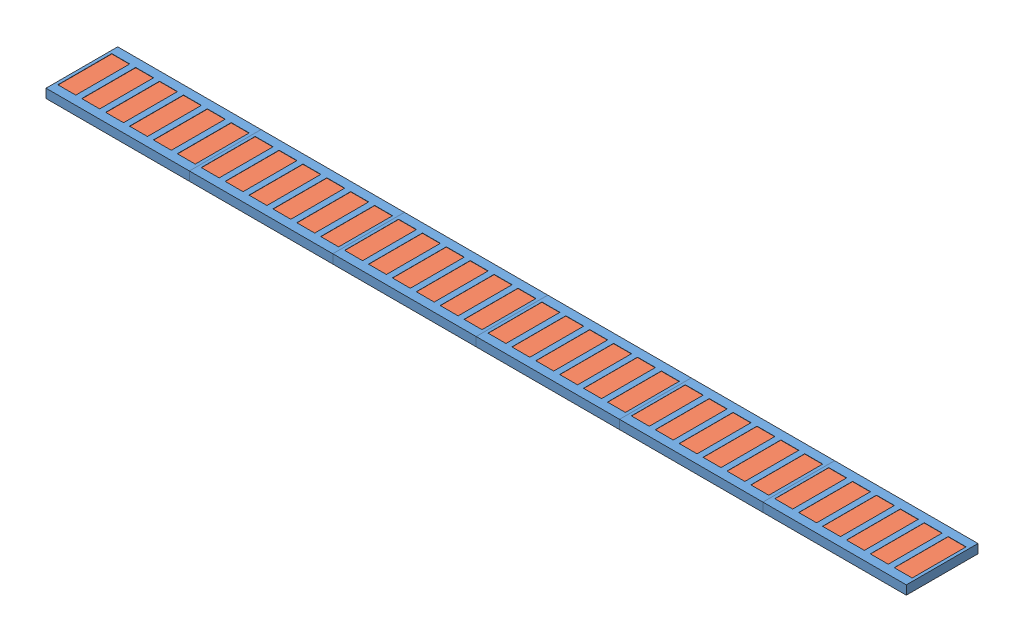
SolidWorks assembly МагнитнаяДорожка_10, configuration По умолчанию. Lengths in mm.
Overall size (480 11.1 40).
42 component instances, 2 part files, 9 mates.
Components (placement in the parent):
- magnete plate-1: magnete plate [По умолчанию] at (0.835 0 0) size (80 11.1 40)
- magnete plate-2: magnete plate [По умолчанию] at (80.835 0 0) size (80 11.1 40)
- magnete plate-3: magnete plate [По умолчанию] at (160.835 0 0) size (80 11.1 40)
- magnete plate-4: magnete plate [По умолчанию] at (240.835 0 0) size (80 11.1 40)
- magnete_30-1: magnete_30 [По умолчанию] at (-32.455 2.9 0) x (0 0 -1) z (1 0 0) size (30 2 10)
- magnete_30-2: magnete_30 [По умолчанию] at (-19.125 2.9 0) x (0 0 -1) z (1 0 0) size (30 2 10)
- magnete_30-3: magnete_30 [По умолчанию] at (-5.795 2.9 0) x (0 0 -1) z (1 0 0) size (30 2 10)
- magnete_30-4: magnete_30 [По умолчанию] at (7.535 2.9 0) x (0 0 -1) z (1 0 0) size (30 2 10)
- magnete_30-5: magnete_30 [По умолчанию] at (20.865 2.9 0) x (0 0 -1) z (1 0 0) size (30 2 10)
- magnete_30-6: magnete_30 [По умолчанию] at (34.195 2.9 0) x (0 0 -1) z (1 0 0) size (30 2 10)
- magnete_30-7: magnete_30 [По умолчанию] at (47.525 2.9 0) x (0 0 -1) z (1 0 0) size (30 2 10)
- magnete_30-8: magnete_30 [По умолчанию] at (60.855 2.9 0) x (0 0 -1) z (1 0 0) size (30 2 10)
- magnete_30-9: magnete_30 [По умолчанию] at (74.185 2.9 0) x (0 0 -1) z (1 0 0) size (30 2 10)
- magnete_30-10: magnete_30 [По умолчанию] at (87.515 2.9 0) x (0 0 -1) z (1 0 0) size (30 2 10)
- magnete_30-11: magnete_30 [По умолчанию] at (100.845 2.9 0) x (0 0 -1) z (1 0 0) size (30 2 10)
- magnete_30-12: magnete_30 [По умолчанию] at (114.175 2.9 0) x (0 0 -1) z (1 0 0) size (30 2 10)
- magnete_30-13: magnete_30 [По умолчанию] at (127.505 2.9 0) x (0 0 -1) z (1 0 0) size (30 2 10)
- magnete_30-14: magnete_30 [По умолчанию] at (140.835 2.9 0) x (0 0 -1) z (1 0 0) size (30 2 10)
- magnete_30-15: magnete_30 [По умолчанию] at (154.165 2.9 0) x (0 0 -1) z (1 0 0) size (30 2 10)
- magnete_30-16: magnete_30 [По умолчанию] at (167.495 2.9 0) x (0 0 -1) z (1 0 0) size (30 2 10)
- magnete_30-17: magnete_30 [По умолчанию] at (180.825 2.9 0) x (0 0 -1) z (1 0 0) size (30 2 10)
- magnete_30-18: magnete_30 [По умолчанию] at (194.155 2.9 0) x (0 0 -1) z (1 0 0) size (30 2 10)
- magnete_30-19: magnete_30 [По умолчанию] at (207.485 2.9 0) x (0 0 -1) z (1 0 0) size (30 2 10)
- magnete_30-20: magnete_30 [По умолчанию] at (220.815 2.9 0) x (0 0 -1) z (1 0 0) size (30 2 10)
- magnete_30-21: magnete_30 [По умолчанию] at (234.145 2.9 0) x (0 0 -1) z (1 0 0) size (30 2 10)
- magnete_30-22: magnete_30 [По умолчанию] at (247.475 2.9 0) x (0 0 -1) z (1 0 0) size (30 2 10)
- magnete_30-23: magnete_30 [По умолчанию] at (260.805 2.9 0) x (0 0 -1) z (1 0 0) size (30 2 10)
- magnete_30-24: magnete_30 [По умолчанию] at (274.135 2.9 0) x (0 0 -1) z (1 0 0) size (30 2 10)
- magnete_30-25: magnete_30 [По умолчанию] at (287.465 2.9 0) x (0 0 -1) z (1 0 0) size (30 2 10)
- magnete_30-26: magnete_30 [По умолчанию] at (300.795 2.9 0) x (0 0 -1) z (1 0 0) size (30 2 10)
- magnete_30-27: magnete_30 [По умолчанию] at (314.125 2.9 0) x (0 0 -1) z (1 0 0) size (30 2 10)
- magnete_30-28: magnete_30 [По умолчанию] at (327.455 2.9 0) x (0 0 -1) z (1 0 0) size (30 2 10)
- magnete_30-29: magnete_30 [По умолчанию] at (340.785 2.9 0) x (0 0 -1) z (1 0 0) size (30 2 10)
- magnete_30-30: magnete_30 [По умолчанию] at (354.115 2.9 0) x (0 0 -1) z (1 0 0) size (30 2 10)
- magnete_30-31: magnete_30 [По умолчанию] at (367.445 2.9 0) x (0 0 -1) z (1 0 0) size (30 2 10)
- magnete_30-32: magnete_30 [По умолчанию] at (380.775 2.9 0) x (0 0 -1) z (1 0 0) size (30 2 10)
- magnete_30-33: magnete_30 [По умолчанию] at (394.105 2.9 0) x (0 0 -1) z (1 0 0) size (30 2 10)
- magnete_30-34: magnete_30 [По умолчанию] at (407.435 2.9 0) x (0 0 -1) z (1 0 0) size (30 2 10)
- magnete_30-35: magnete_30 [По умолчанию] at (420.765 2.9 0) x (0 0 -1) z (1 0 0) size (30 2 10)
- magnete_30-36: magnete_30 [По умолчанию] at (434.095 2.9 0) x (0 0 -1) z (1 0 0) size (30 2 10)
- magnete plate-5: magnete plate [По умолчанию] at (320.835 0 0) size (80 11.1 40)
- magnete plate-6: magnete plate [По умолчанию] at (400.835 0 0) size (80 11.1 40)
Mates (geometry in assembly coordinates):
- Совпадение1: coincident aligned: plane of magnete plate edge-1 through (40.835 5 20) normal (0 0 1); plane of magnete plate-1 through (120.835 5 20) normal (0 0 1)
- Совпадение2: coincident anti-aligned: plane of magnete plate edge-1 through (40.835 5 20) normal (1 0 0); plane of magnete plate-1 through (40.835 5 20) normal (-1 0 0)
- Совпадение3: coincident aligned: plane of magnete plate edge-1 through (0 5 0) normal (0 1 0); plane of magnete plate-1 through (80.835 5 0) normal (0 1 0)
- Совпадение4: coincident anti-aligned: plane of magnete plate-4 through (360.835 5 20) normal (1 0 0); plane of magnete plate edge-2 through (360.835 5 -20) normal (-1 0 0)
- Совпадение6: coincident aligned: plane of magnete plate-4 through (320.835 5 0) normal (0 1 0); plane of magnete plate edge-2 through (401.67 5 0) normal (0 1 0)
- Совпадение7: coincident aligned: plane of magnete plate-4 through (360.835 5 20) normal (0 0 1); plane of magnete plate edge-2 through (360.835 5 20) normal (0 0 1)
- Расстояние1: distance = 0.05 mm anti-aligned: plane of magnete_30-1 through (-37.455 4.9 -15) normal (-1 0 0); plane of magnete plate-1 through (-37.505 2.9 -15.05) normal (1 0 0)
- Расстояние2: distance = 0.05 mm anti-aligned: plane of magnete_30-1 through (-27.455 4.9 15) normal (0 0 1); plane of magnete plate edge-1 through (-37.505 2.9 15.05) normal (0 0 -1)
- Совпадение10: coincident anti-aligned: plane of magnete plate edge-1 through (0 2.9 0) normal (0 1 0); plane of magnete_30-1 through (-32.455 2.9 0) normal (0 -1 0)
